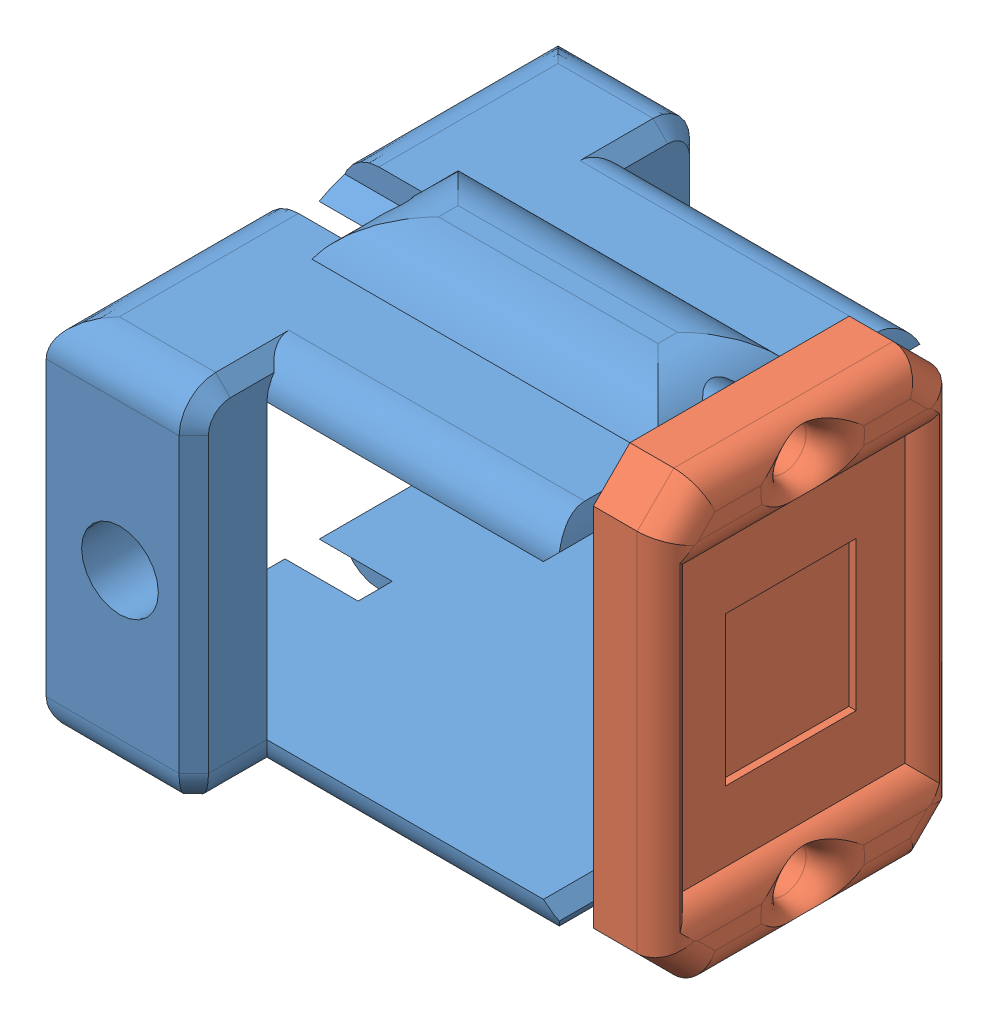
SolidWorks assembly Assem2, configuration Default. Lengths in mm.
Overall size (34.92 30 35).
2 component instances, 2 part files, 2 mates.
Components (placement in the parent):
- sE1X Y idler-2: sE1X Y idler [Default] at (-1.6239 3.9342 14.5086) size (30 30 35)
- sE1X Y idler t-bracket-1: sE1X Y idler t-bracket [Default] at (10.7915 3.9342 27.0086) size (5 30 20)
Mates (geometry in assembly coordinates):
- Coincident3: coincident: line of sE1X Y idler-2 through (10.7915 14.8497 39.3349) axis (0 0 -1); plane of sE1X Y idler t-bracket-1 through (10.7915 3.9342 27.0086) normal (-1 0 0)
- Coincident4: coincident aligned: cylinder of sE1X Y idler-2 through (-19.124 16.4342 27.0086) axis (1 0 0) radius 1.55; circle of sE1X Y idler t-bracket-1
